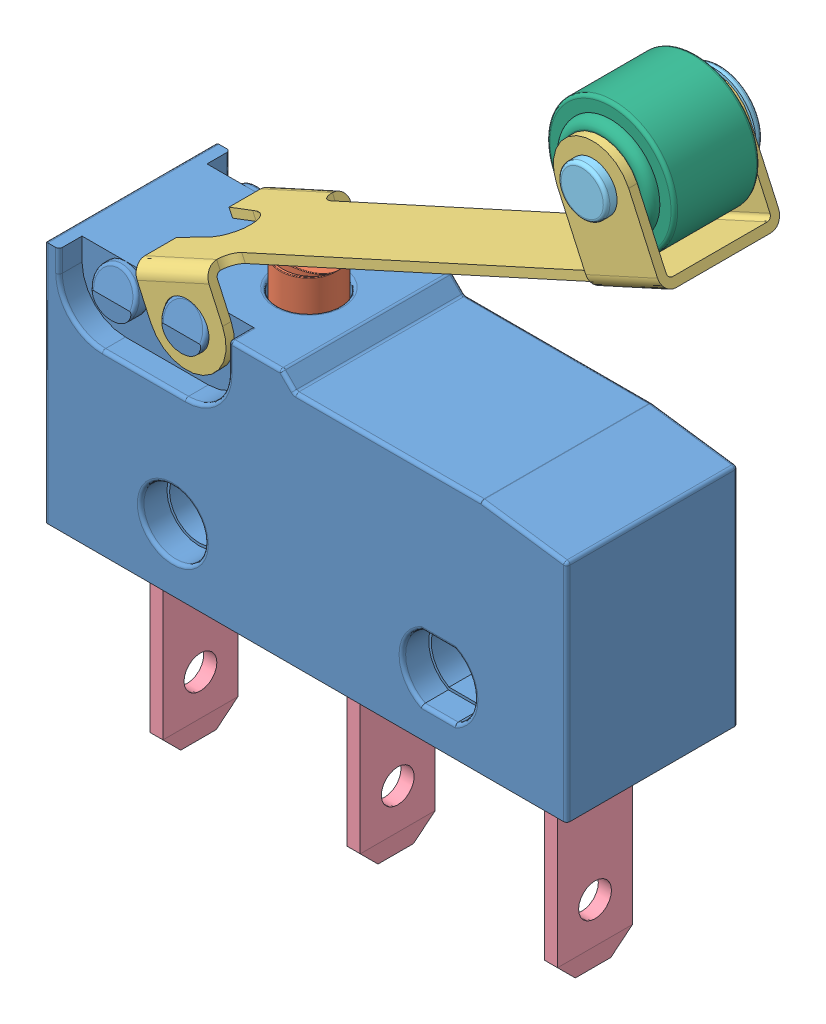
SolidWorks assembly Switch_com_espaçamento, configuration Default. Lengths in mm.
Overall size (23.77 31.44 6.5).
8 component instances, 6 part files, 18 mates.
Components (placement in the parent):
- corpo-1: corpo [Default] at (1.1317 -3.5508 1.8152) size (19.85 9.5 6.5)
- botao-1: botao [Default] at (-1.9933 4.4492 1.8152) size (2.28 2.9 2.2)
- haste-1: haste [Default] at (3.8671 10.3945 1.8152) x (-0.910275 -0.414005 0) z (0 0 -1) size (21.6 7.58 5.4)
- pinsw-1: pinsw [Default] at (-6.3683 -11.0508 1.8152) x (0 0 -1) z (1 0 0) size (2.85 8.5 0.5)
- pino_haste-1: pino_haste [Default] at (11.0958 16.9642 1.8152) x (-0.923728 -0.383049 0) z (0 0 -1) size (3.2 3.2 5.25)
- roda-1: roda [Default] at (11.0958 16.9642 1.8152) x (0.676521 -0.736423 0) z (0 0 -1) size (4.85 4.85 3.95)
- pinsw-3: pinsw [Default] at (1.1317 -11.0508 1.8152) x (0 0 -1) z (1 0 0) size (2.85 8.5 0.5)
- pinsw-5: pinsw [Default] at (8.6317 -11.0508 1.8152) x (0 0 -1) z (1 0 0) size (2.85 8.5 0.5)
Mates (geometry in assembly coordinates):
- Concentric1: concentric anti-aligned: cylinder of corpo-1 through (-1.9933 2.9492 1.8152) axis (0 1 0) radius 1.175; cylinder of botao-1 through (-1.9933 7.0492 1.8152) axis (0 -1 0) radius 1.1
- Coincident2: coincident anti-aligned: plane of corpo-1 through (-6.1183 -2.5508 3.2402) normal (-1 0 0); plane of pinsw-1 through (-6.1183 -2.5508 0.3902) normal (1 0 0)
- Coincident3: coincident anti-aligned: plane of corpo-1 through (-6.6183 -2.5508 0.3902) normal (0 0 1); plane of pinsw-1 through (-6.1183 -11.0508 0.3902) normal (0 0 -1)
- Coincident4: coincident anti-aligned: plane of corpo-1 through (-6.6183 -2.5508 0.3902) normal (0 -1 0); plane of pinsw-1 through (-6.1183 -2.5508 3.2402) normal (0 1 0)
- Coincident5: coincident anti-aligned: plane of corpo-1 through (1.3817 -2.5508 3.2402) normal (-1 0 0); plane of pinsw-3 through (1.3817 -2.5508 0.3902) normal (1 0 0)
- Coincident6: coincident anti-aligned: plane of corpo-1 through (0.8817 -2.5508 0.3902) normal (0 0 1); plane of pinsw-3 through (1.3817 -11.0508 0.3902) normal (0 0 -1)
- Coincident7: coincident anti-aligned: plane of corpo-1 through (0.8817 -2.5508 0.3902) normal (0 -1 0); plane of pinsw-3 through (1.3817 -2.5508 3.2402) normal (0 1 0)
- Coincident8: coincident anti-aligned: plane of corpo-1 through (8.8817 -2.5508 3.2402) normal (-1 0 0); plane of pinsw-5 through (8.8817 -2.5508 0.3902) normal (1 0 0)
- Coincident9: coincident anti-aligned: plane of corpo-1 through (8.3817 -2.5508 0.3902) normal (0 0 1); plane of pinsw-5 through (8.8817 -11.0508 0.3902) normal (0 0 -1)
- Coincident10: coincident anti-aligned: plane of corpo-1 through (8.3817 -2.5508 0.3902) normal (0 -1 0); plane of pinsw-5 through (8.8817 -2.5508 3.2402) normal (0 1 0)
- Coincident11: coincident anti-aligned: circle of haste-1; cylinder of roda-1 through (11.0958 16.9642 3.7902) axis (0 0 -1) radius 0.75
- Coincident12: coincident anti-aligned: plane of haste-1 through (11.8402 18.9506 -0.1598) normal (0 0 1); plane of roda-1 through (11.0958 16.9642 -0.1598) normal (0 0 -1)
- Concentric2: concentric anti-aligned: cylinder of pino_haste-1 through (11.0958 16.9642 -0.4848) axis (0 0 1) radius 0.75; cylinder of roda-1 through (11.0958 16.9642 3.7902) axis (0 0 -1) radius 0.75
- Coincident13: coincident anti-aligned: plane of haste-1 through (13.6308 15.0136 -0.4848) normal (0 0 -1); plane of pino_haste-1 through (11.0958 16.9642 -0.4848) normal (0 0 1)
- Concentric3: concentric anti-aligned: cylinder of haste-1 through (-3.9412 5.0992 4.5152) axis (0 0 -1) radius 0.85; cylinder of corpo-1 through (-3.9412 5.0992 -1.0848) axis (0 0 1) radius 0.85
- Coincident14: coincident anti-aligned: plane of corpo-1 through (-6.5933 4.8492 -0.5598) normal (0 0 -1); plane of haste-1 through (-1.9548 4.3548 -0.5598) normal (0 0 1)
- Tangent1: tangent anti-aligned: cylinder of botao-1 through (-1.9933 4.7492 0.7152) axis (0 0 1) radius 2.55; plane of haste-1 through (10.807 13.3723 3.7652) normal (0.414005 -0.910275 0)
- LimitDistance1: limit distance = 9.09 mm anti-aligned: cylinder of roda-1 through (11.0958 16.9642 0.1902) axis (0 0 1) radius 2.425; plane of corpo-1 through (0.7067 5.4492 -1.4349) normal (0 1 0)
